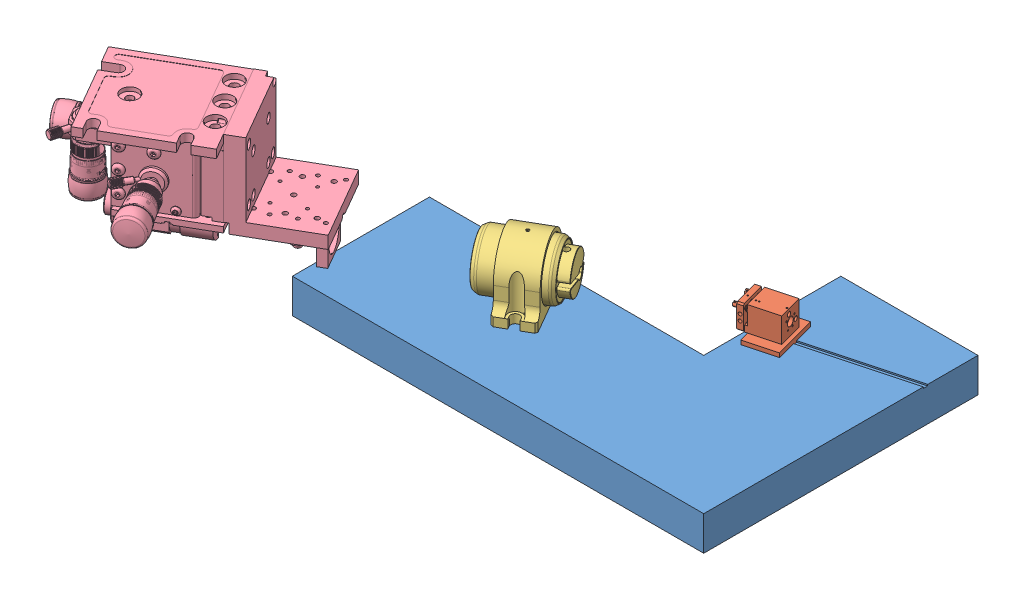
SolidWorks assembly fiber_launch_deflector, configuration Default. Lengths in mm.
Overall size (437.7 122.22 318.92).
4 component instances, 4 part files, 7 mates.
Components (placement in the parent):
- deflector_holder_plate-1: deflector_holder_plate [Default] at origin size (300 25 200)
- ASM003_fast_stage-1: ASM003_fast_stage [Default] at (-12.8928 39.6882 -38.0241) x (-0.965926 0 0.258819) z (-0.258819 0 -0.965926) size (32.45 22.3 32)
- 110-21053-0003 REV A (DEFEATURED)-1: 110-21053-0003 REV A (DEFEATURED) [Default] at (-101.8016 47.225 31.0739) x (0.866025 0 -0.5) z (0.5 0 0.866025) size (55.94 44.23 55)
- MBT621D_fiber_stage-1: MBT621D_fiber_stage [Default] at (-589.5078 116.225 347.4077) x (-0.866025 0 0.5) z (0.5 0 0.866025) size (157 87.61 116.56)
Mates (geometry in assembly coordinates):
- Coincident1: coincident anti-aligned: line of deflector_holder_plate-1 through (0 25 -33.4471) axis (0.965926 0 -0.258819); line of ASM003_fast_stage-1 through (25.298 25 -40.2257) axis (-0.965926 0 0.258819)
- Coincident2: coincident anti-aligned: plane of deflector_holder_plate-1 through (0 25 0) normal (0 1 0); plane of ASM003_fast_stage-1 through (29.0509 25 -26.2197) normal (0 -1 0)
- Coincident3: coincident anti-aligned: plane of deflector_holder_plate-1 through (0 25 0) normal (0 1 0); plane of 110-21053-0003 REV A (DEFEATURED)-1 through (-99.0924 25 4.1063) normal (0 -1 0)
- Parallel1: parallel aligned: line of deflector_holder_plate-1 through (15 25 -39.0192) axis (-0.866025 0 0.5); line of 110-21053-0003 REV A (DEFEATURED)-1 through (-102.9422 25 -0.0218) axis (-0.866025 0 0.5)
- Parallel2: parallel aligned: line of deflector_holder_plate-1 through (15 25 -39.0192) axis (-0.866025 0 0.5); line of MBT621D_fiber_stage-1 through (-273.0781 -27.775 79.1536) axis (-0.866025 0 0.5)
- Concentric3: concentric aligned: circle of 110-21053-0003 REV A (DEFEATURED)-1; circle of MBT621D_fiber_stage-1
- Parallel3: parallel aligned: plane of deflector_holder_plate-1 through (0 25 0) normal (0 1 0); plane of MBT621D_fiber_stage-1 through (-304.4346 122.025 59.7426) normal (0 1 0)
